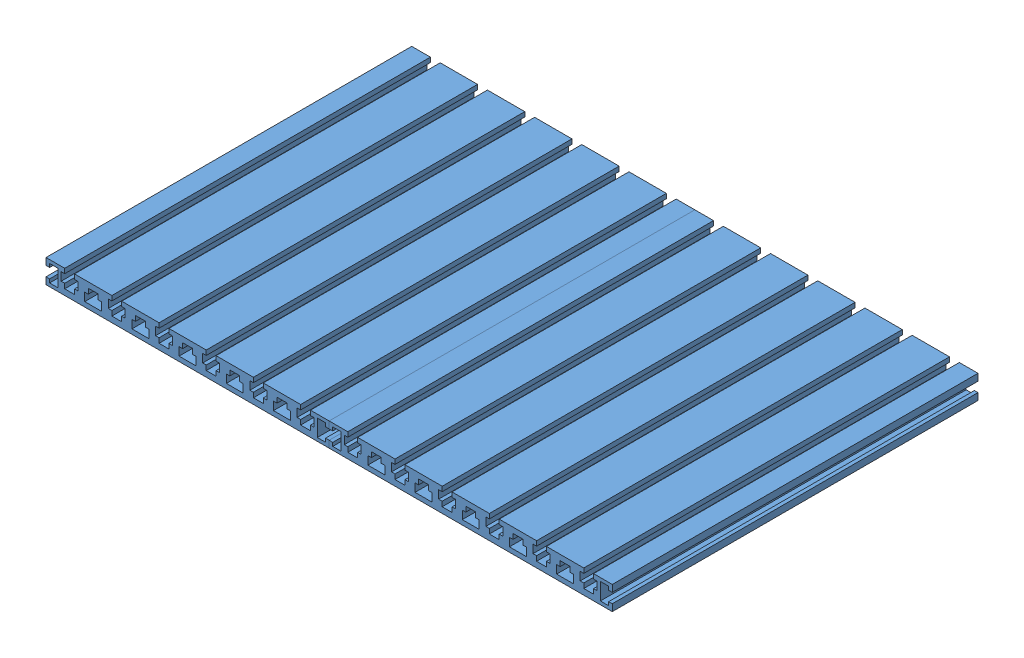
SolidWorks assembly Assem1, configuration Default. Lengths in mm.
Overall size (480 20 310).
2 component instances, 1 part files, 3 mates.
Components (placement in the parent):
- extrusion 20240x310-1: extrusion 20240x310 [Default] at (26.8604 177.7216 119.0048) size (240 20 310)
- extrusion 20240x310-2: extrusion 20240x310 [Default] at (266.8604 177.7216 119.0048) size (240 20 310)
Mates (geometry in assembly coordinates):
- Coincident2: coincident: plane of extrusion 20240x310-1 through (26.8604 187.7216 429.0048) normal (0 1 0); plane of extrusion 20240x310-2 through (374.0996 187.7216 429.0048) normal (0 1 0)
- Coincident3: coincident: plane of extrusion 20240x310-1 through (26.8604 177.7216 429.0048) normal (0 0 1); plane of extrusion 20240x310-2 through (374.0996 177.7216 429.0048) normal (0 0 1)
- Coincident4: coincident anti-aligned: plane of extrusion 20240x310-1 through (146.8604 177.7216 429.0048) normal (1 0 0); plane of extrusion 20240x310-2 through (146.8604 177.7216 429.0048) normal (-1 0 0)
